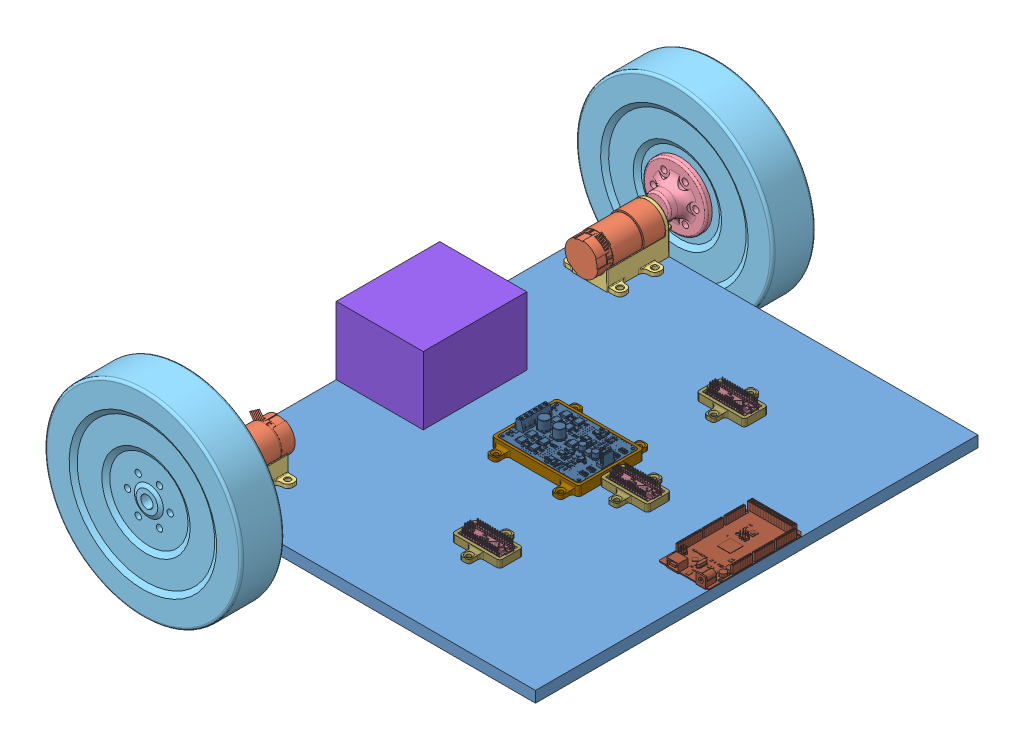
SolidWorks assembly assem_drive, configuration Default. Lengths in mm.
Overall size (476.24 277.58 593.52).
32 component instances, 16 part files, 37 mates.
Components (placement in the parent):
- drivePlatform-1: drivePlatform [Default] at (226.3708 293.8304 481.1534) size (381 11.46 457.2)
- assem_wheelDrive-1: assem_wheelDrive [Default] at (79.4208 330.2858 705.7534) size (277.58 277.58 140.26)
  - gearmotor_Pololu_30-1-1: gearmotor_Pololu_30-1 [Default] at (19.925 0 -19.925) x (-1 0 0) z (0 0 1) size (36.88 41.23 90.1)
  - motorMount-1: motorMount [Default] at origin size (61 43.5 64)
  - hub_v2-1: hub_v2 [Default] at (0 7 34) x (0 -1 0) z (1 0 0) size (66 44 66)
  - wheel-1: wheel [Default] at (0 7 49.934) x (0 0 -1) z (0.5 0.866025 0) size (44.45 203.2 203.2)
  - 93365A142_HEAT-SET INSERTS FOR PLASTICS-1: 93365A142_HEAT-SET INSERTS FOR PLASTICS [93365A142] at (0 -8 19) x (1 0 0) z (0 0 -1) size (6.35 8.46 6.35)
  - 91772A197_18-8 SS PAN HEAD PHILLIPS MACHINE SCREW-1: 91772A197_18-8 SS PAN HEAD PHILLIPS MACHINE SCREW [91772A197] at (0 4.6 19) x (-0.300305 0 -0.953843) z (0 -1 0) size (8.18 8.18 22.32)
- assem_wheelDrive-2: assem_wheelDrive [Default] at (79.4208 330.2858 256.5534) x (-1 0 0) z (0 0 -1) size (277.58 277.58 140.26)
  - gearmotor_Pololu_30-1-1: gearmotor_Pololu_30-1 [Default] at (19.925 0 -19.925) x (-1 0 0) z (0 0 1) size (36.88 41.23 90.1)
  - motorMount-1: motorMount [Default] at origin size (61 43.5 64)
  - hub_v2-1: hub_v2 [Default] at (0 7 34) x (0 -1 0) z (1 0 0) size (66 44 66)
  - wheel-1: wheel [Default] at (0 7 49.934) x (0 0 -1) z (0.5 0.866025 0) size (44.45 203.2 203.2)
  - 93365A142_HEAT-SET INSERTS FOR PLASTICS-1: 93365A142_HEAT-SET INSERTS FOR PLASTICS [93365A142] at (0 -8 19) x (1 0 0) z (0 0 -1) size (6.35 8.46 6.35)
  - 91772A197_18-8 SS PAN HEAD PHILLIPS MACHINE SCREW-1: 91772A197_18-8 SS PAN HEAD PHILLIPS MACHINE SCREW [91772A197] at (0 4.6 19) x (-0.300305 0 -0.953843) z (0 -1 0) size (8.18 8.18 22.32)
- slaBattery_ExpertPower-1: slaBattery_ExpertPower [Default] at (125.7868 305.2858 427.6864) x (0 0 1) z (0 -1 0) size (106.93 89.92 70.1)
- motorDriverMount-1: motorDriverMount [Default] at (176.5868 305.2858 514.9034) size (90 10 91.5)
- motorController_Cytron-1: motorController_Cytron [Default] at (179.2958 313.7858 532.3344) x (1 0 0) z (0 1 0) size (84.58 61.72 14.9)
- arduinoMega_Elegoo-1: arduinoMega_Elegoo [Default] at (391.4795 305.2858 481.6974) x (0 0 1) z (-1 0 0) size (100 11.65 51.63)
- assem_mountedArduinoNano-1: assem_mountedArduinoNano [Default] at (246.9731 285.945 321.0619) size (49.6 14.1 48.3)
  - arduinoNanoMount-1: arduinoNanoMount [Default] at (-6.7023 19.3409 45.7916) size (49.6 7.5 48.3)
  - arduinoNano_Elegoo-1: arduinoNano_Elegoo [Default] at (0.3177 23.3409 41.2616) size (45 11.95 18)
- assem_mountedArduinoNano-2: assem_mountedArduinoNano [Default] at (246.9731 285.945 573.9619) size (49.6 14.1 48.3)
  - arduinoNanoMount-1: arduinoNanoMount [Default] at (-6.7023 19.3409 45.7916) size (49.6 7.5 48.3)
  - arduinoNano_Elegoo-1: arduinoNano_Elegoo [Default] at (0.3177 23.3409 41.2616) size (45 11.95 18)
- assem_mountedArduinoNano-3: assem_mountedArduinoNano [Default] at (273.2891 285.945 447.5119) size (49.6 14.1 48.3)
  - arduinoNanoMount-1: arduinoNanoMount [Default] at (-6.7023 19.3409 45.7916) size (49.6 7.5 48.3)
  - arduinoNano_Elegoo-1: arduinoNano_Elegoo [Default] at (0.3177 23.3409 41.2616) size (45 11.95 18)
- assem_caster-1: assem_caster [Default] at (394.416 253.1185 462.5686) x (0 0 1) z (-1 0 0) size (48.88 70.33 81.97)
  - casterMountingPlate-1: casterMountingPlate [Default] at (18.5848 38.712 45.8952) size (45 10.47 60.5)
  - casterSwivel-1: casterSwivel [Default] at (18.5848 -9.7561 45.8952) x (0.095884 0 -0.995393) z (0.995393 0 0.095884) size (53 41 44)
  - casterWheel-1: casterWheel [Default] at (8.1134 -3.7561 68.9976) x (0.046117 0.87674 -0.478748) z (0.084065 -0.480964 -0.872701) size (38.1 40 38.1)
Mates (geometry in assembly coordinates):
- Concentric1: concentric: circle of drivePlatform-1; circle of assem_wheelDrive-1/motorMount-1
- Concentric2: concentric: circle of drivePlatform-1; circle of assem_wheelDrive-1/motorMount-1
- Concentric3: concentric: circle of drivePlatform-1; circle of assem_wheelDrive-2/motorMount-1
- Concentric4: concentric: circle of drivePlatform-1; circle of assem_wheelDrive-2/motorMount-1
- Coincident8: coincident: plane of drivePlatform-1 through (226.3708 305.2858 481.1534) normal (0 1 0); plane of assem_wheelDrive-2/motorMount-1 through (97.9208 305.2858 252.5534) normal (0 -1 0)
- Coincident9: coincident: plane of drivePlatform-1 through (226.3708 305.2858 481.1534) normal (0 1 0); plane of assem_wheelDrive-1/motorMount-1 through (60.9208 305.2858 709.7534) normal (0 -1 0)
- Coincident10: coincident: plane of drivePlatform-1 through (226.3708 305.2858 481.1534) normal (0 1 0); plane of slaBattery_ExpertPower-1 through (35.8708 305.2858 427.6864) normal (0 -1 0)
- Distance1: distance = 0 mm: plane of slaBattery_ExpertPower-1 through (35.8708 305.2858 427.6864) normal (-1 0 0); plane of drivePlatform-1 through (35.8708 305.2858 709.7534) normal (-1 0 0)
- Width1: width: plane of drivePlatform-1 through (35.8708 305.2858 709.7534) normal (0 0 1); plane of drivePlatform-1 through (35.8708 305.2858 252.5534) normal (0 0 -1); plane of slaBattery_ExpertPower-1 through (35.8708 305.2858 427.6864) normal (0 0 -1); plane of slaBattery_ExpertPower-1 through (35.8708 305.2858 534.6204) normal (0 0 1)
- Coincident12: coincident: plane of drivePlatform-1 through (226.3708 305.2858 481.1534) normal (0 1 0); plane of ? through (315.2708 305.2858 404.9534) normal (0 -1 0)
- Width2: width: plane of drivePlatform-1 through (35.8708 305.2858 252.5534) normal (0 0 -1); plane of drivePlatform-1 through (35.8708 305.2858 709.7534) normal (0 0 1); plane of ? through (315.2708 305.2858 404.9534) normal (0 0 -1); plane of ? through (315.2708 305.2858 557.3534) normal (0 0 1)
- Distance2: distance = 101.6 mm: plane of ? through (315.2708 305.2858 404.9534) normal (1 0 0); plane of drivePlatform-1 through (416.8708 305.2858 709.7534) normal (1 0 0)
- Coincident13: coincident: plane of drivePlatform-1 through (226.3708 305.2858 481.1534) normal (0 1 0); plane of motorDriverMount-1 through (176.5868 305.2858 514.9034) normal (0 -1 0)
- Concentric6: concentric: circle of motorDriverMount-1; circle of motorController_Cytron-1
- Concentric7: concentric: circle of motorDriverMount-1; circle of motorController_Cytron-1
- Coincident14: coincident: plane of motorDriverMount-1 through (176.5868 313.7858 514.9034) normal (0 1 0); plane of motorController_Cytron-1 through (182.2168 313.7858 512.0144) normal (0 -1 0)
- Width3: width: plane of motorDriverMount-1 through (176.5868 315.2858 514.9034) normal (0 0 1); plane of motorDriverMount-1 through (266.5868 315.2858 447.4034) normal (0 0 -1); plane of drivePlatform-1 through (35.8708 305.2858 252.5534) normal (0 0 -1); plane of drivePlatform-1 through (35.8708 305.2858 709.7534) normal (0 0 1)
- Distance3: distance = 50.8 mm: plane of motorDriverMount-1 through (176.5868 315.2858 447.4034) normal (-1 0 0); plane of slaBattery_ExpertPower-1 through (125.7868 305.2858 427.6864) normal (1 0 0)
- Coincident15: coincident: plane of drivePlatform-1 through (226.3708 305.2858 481.1534) normal (0 1 0); plane of arduinoMega_Elegoo-1 through (391.4795 305.2858 481.6974) normal (0 -1 0)
- Width4: width: plane of arduinoMega_Elegoo-1 through (404.8675 296.2858 530.6095) normal (0 0 1); plane of arduinoMega_Elegoo-1 through (364.9795 306.2858 431.6974) normal (0 0 -1); plane of drivePlatform-1 through (35.8708 305.2858 252.5534) normal (0 0 -1); plane of drivePlatform-1 through (35.8708 305.2858 709.7534) normal (0 0 1)
- Coincident16: coincident: plane of drivePlatform-1 through (416.8708 305.2858 709.7534) normal (1 0 0); plane of arduinoMega_Elegoo-1 through (416.8708 296.2858 531.6974) normal (1 0 0)
- Concentric9: concentric: cylinder of assem_wheelDrive-2/hub_v2-1 through (79.4208 500337.2858 237.5534) axis (0 -1 0) radius 2.675; cylinder of ? through (79.4208 330.2106 237.5534) axis (0 -1 0) radius 2.6416
- Coincident17: coincident: plane of assem_wheelDrive-2/hub_v2-1 through (79.4208 322.2858 237.5534) normal (0 -1 0); plane of ? through (79.4208 322.2858 237.5534) normal (0 -1 0)
- Concentric10: concentric: circle of ?; cylinder of ? through (79.4208 334.8858 237.5534) axis (0 1 0) radius 4.0894
- Coincident19: coincident: plane of assem_wheelDrive-2/gearmotor_Pololu_30-1-1 through (77.6208 334.8858 246.5534) normal (0 -1 0); plane of ? through (79.4208 334.8858 237.5534) normal (0 1 0)
- Coincident20: coincident: plane of assem_mountedArduinoNano-1/arduinoNanoMount-1 through (289.8708 312.7858 366.8534) normal (1 0 0); plane of assem_mountedArduinoNano-2/arduinoNanoMount-1 through (289.8708 312.7858 619.7534) normal (1 0 0)
- Distance4: distance = 228.6 mm: plane of assem_mountedArduinoNano-2/arduinoNanoMount-1 through (289.8708 312.7858 595.4534) normal (0 0 -1); plane of assem_mountedArduinoNano-1/arduinoNanoMount-1 through (240.2708 312.7858 366.8534) normal (0 0 1)
- Width5: width: plane of drivePlatform-1 through (35.8708 305.2858 709.7534) normal (0 0 1); plane of drivePlatform-1 through (35.8708 305.2858 252.5534) normal (0 0 -1); plane of assem_mountedArduinoNano-1/arduinoNanoMount-1 through (289.8708 312.7858 342.5534) normal (0 0 -1); plane of assem_mountedArduinoNano-2/arduinoNanoMount-1 through (240.2708 312.7858 619.7534) normal (0 0 1)
- Coincident21: coincident: plane of drivePlatform-1 through (226.3708 305.2858 481.1534) normal (0 1 0); plane of assem_mountedArduinoNano-1/arduinoNanoMount-1 through (240.2708 305.2858 366.8534) normal (0 -1 0)
- Coincident22: coincident: plane of drivePlatform-1 through (226.3708 305.2858 481.1534) normal (0 1 0); plane of assem_mountedArduinoNano-2/arduinoNanoMount-1 through (240.2708 305.2858 619.7534) normal (0 -1 0)
- Coincident23: coincident: plane of drivePlatform-1 through (226.3708 305.2858 481.1534) normal (0 1 0); plane of assem_mountedArduinoNano-3/arduinoNanoMount-1 through (266.5868 305.2858 493.3034) normal (0 -1 0)
- Distance6: distance = 127 mm: plane of assem_mountedArduinoNano-2/arduinoNanoMount-1 through (289.8708 312.7858 619.7534) normal (1 0 0); plane of drivePlatform-1 through (416.8708 305.2858 709.7534) normal (1 0 0)
- Coincident25: coincident: plane of motorDriverMount-1 through (266.5868 315.2858 514.9034) normal (1 0 0); plane of assem_mountedArduinoNano-3/arduinoNanoMount-1 through (266.5868 312.7858 469.0034) normal (-1 0 0)
- Width6: width: plane of assem_mountedArduinoNano-3/arduinoNanoMount-1 through (266.5868 312.7858 493.3034) normal (0 0 1); plane of assem_mountedArduinoNano-3/arduinoNanoMount-1 through (316.1868 312.7858 469.0034) normal (0 0 -1); plane of motorDriverMount-1 through (266.5868 315.2858 447.4034) normal (0 0 -1); plane of motorDriverMount-1 through (176.5868 315.2858 514.9034) normal (0 0 1)
- Coincident26: coincident: plane of drivePlatform-1 through (226.3708 293.8304 481.1534) normal (0 -1 0); plane of assem_caster-1/casterMountingPlate-1 through (348.5208 293.8304 481.1534) normal (0 1 0)
- Width7: width: plane of drivePlatform-1 through (35.8708 305.2858 252.5534) normal (0 0 -1); plane of drivePlatform-1 through (35.8708 305.2858 709.7534) normal (0 0 1); plane of assem_caster-1/casterMountingPlate-1 through (378.7708 293.8304 503.6534) normal (0 0 1); plane of assem_caster-1/casterMountingPlate-1 through (378.7708 293.8304 458.6534) normal (0 0 -1)
- Distance7: distance = 38.1 mm: plane of assem_caster-1/casterMountingPlate-1 through (378.7708 293.8304 458.6534) normal (1 0 0); plane of drivePlatform-1 through (416.8708 305.2858 709.7534) normal (1 0 0)
